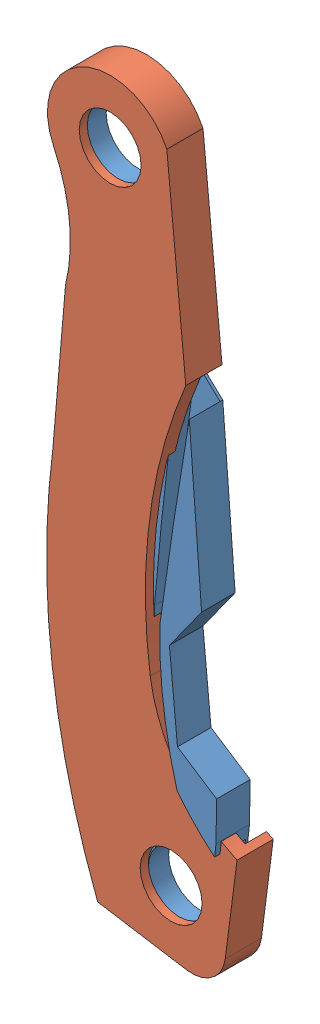
SolidWorks assembly Handle LH, configuration Default. Lengths in mm.
Overall size (19.54 69.98 3.94).
2 component instances, 2 part files, 1 mates.
Components (placement in the parent):
- Interior Handle-1: Interior Handle [Default] at origin size (15.04 67.31 3.17)
- Exterior-1: Exterior [LH] at (-77.4141 -47.8306 -0.762) x (0.999921 -0.012606 0) z (0 0 1) size (18.66 69.75 3.43)
Mates (geometry in assembly coordinates):
- Concentric8: concentric: cylinder of Interior Handle-1 through (-19.0739 29.4778 1.905) axis (0 0 -1) radius 3.048; cylinder of Exterior-1 through (-19.0739 29.4778 2.668) axis (0 0 -1) radius 2.9337
